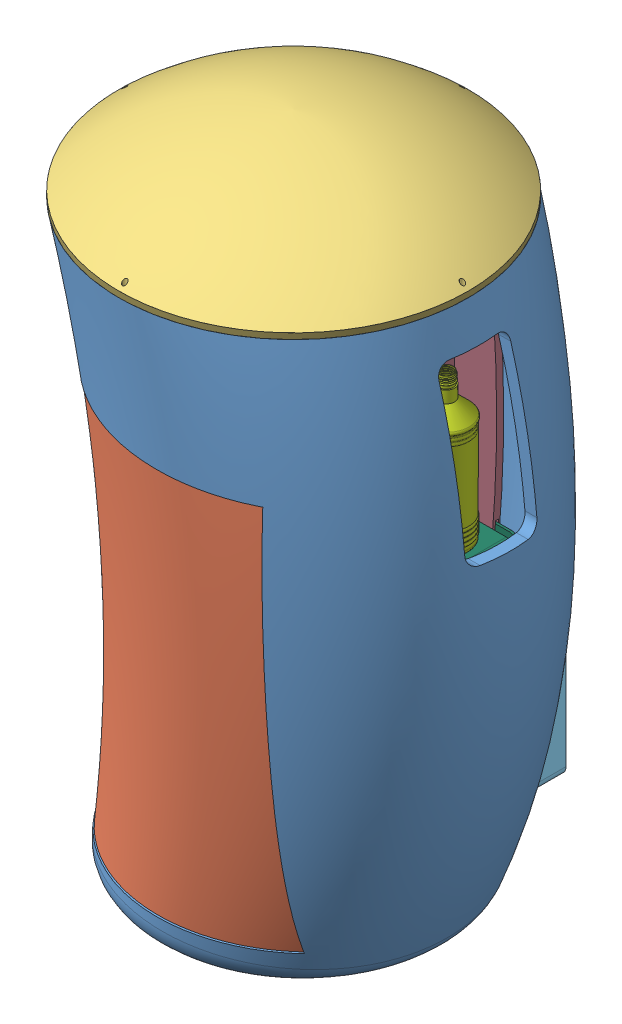
SolidWorks assembly Final assembly, configuration Default. Lengths in mm.
Overall size (714.59 1130 678.31).
22 component instances, 15 part files, 9 mates.
Components (placement in the parent):
- body-1: body [Default] at (238.4897 116.9189 1113.8319) size (714.59 1000.01 604.52)
- DooR (2)-1: DooR (2) [Default] at (237.093 116.9189 1110.2554) x (-1 0 0) z (0 0 -1) size (539.09 712.4 312.06)
- head-1: head [Default] at (238.4897 1126.9189 1113.8319) size (600 120 600)
- The shrinker-2: The shrinker [Default] at (195.4435 68.0364 733.0496) size (200 714.8 100)
  - bottle load-1: bottle load [Default] at (69.4638 76.8825 55.0523) x (1 0 0) z (0 0 -1) size (105 16 100)
  - support mat-1: support mat [Default] at (69.4638 54.8825 55.0523) size (142 362 90)
  - pressing point-1: pressing point [Default] at (69.4638 377.6793 55.0523) x (-1 0 0) z (0 0 -1) size (135 357.5 15)
  - Battery Water Bottle HDPE-1: Battery Water Bottle HDPE [Default] at (69.4638 66.0825 55.0523) size (81.4 253.7 81.4)
  - hand-1: hand [Default] at (69.4638 753.6793 55.0523) x (0 0 1) z (1 0 0) size (20 50 200)
  - top_shrinker-2: top_shrinker [Default] at (69.4638 368.6793 55.0523) x (-1 0 0) z (0 -1 0) size (110 90 29)
  - holder-1: holder [Default] at (107.0415 392.6793 55.0523) x (0 0 1) z (0 -1 0) size (30 15 9)
  - holder-2: holder [Default] at (31.8862 392.6793 55.0523) x (0 0 -1) z (0 -1 0) size (30 15 9)
  - guidage-1: guidage [Default] at (116.4638 58.2714 92.0523) x (0.67309 0 -0.73956) z (0.73956 0 0.67309) size (5 360 5)
  - guidage-2: guidage [Default] at (22.4638 58.2301 92.0523) x (0.059609 0 0.998222) z (-0.998222 0 0.059609) size (5 360 5)
  - guidage-3: guidage [Default] at (116.4638 56.8278 18.0523) x (0.363061 0 -0.931765) z (0.931765 0 0.363061) size (5 360 5)
  - guidage-4: guidage [Default] at (22.4638 55.7969 18.0523) x (0.648295 0 -0.761389) z (0.761389 0 0.648295) size (5 360 5)
- plate_for_electronics-1: plate_for_electronics [Default] at (238.4897 1116.9189 1113.8319) size (600 10 600)
- chamber_product2-1: chamber_product2 [Default] at (96.9579 614.8492 1278.3882) x (0 0 -1) z (1 0 0) size (150 398 116)
  - base_product2-1: base_product2 [Default] at (164.5564 96.0696 403.5318) x (-1 0 0) z (0 0 -1) size (142 396 88.73)
  - arbre servo-1: arbre servo [Default] at (85.5564 113.0696 365.5318) x (0 0 -1) z (1 0 0) size (8 8 150)
  - bottle base_product 2-2: bottle base_product 2 [Default] at (164.1814 126.0696 408.5318) x (-1 0 0) z (0 0 1) size (135.25 22 100)
  - Battery Water Bottle HDPE-2: Battery Water Bottle HDPE [Default] at (164.5564 122.7501 403.5318) x (-0.998313 0 -0.058067) z (0.058067 0 -0.998313) size (81.4 253.7 81.4)
Mates (geometry in assembly coordinates):
- Coincident1: coincident anti-aligned: plane of body-1 through (38.4897 881.9189 1113.8319) normal (1 0 0); plane of DooR (2)-1 through (38.4897 881.9189 808.3186) normal (-1 0 0)
- Coincident2: coincident anti-aligned: plane of body-1 through (38.4897 181.9189 1113.8319) normal (0 1 0); plane of DooR (2)-1 through (38.4897 181.9189 808.3186) normal (0 -1 0)
- Coincident9: coincident aligned: plane of body-1 through (238.4897 116.9189 1113.8319) normal (0 -1 0); plane of The shrinker-2/support mat-1 through (319.9074 116.9189 743.1019) normal (0 -1 0)
- Lock1: lock: unknown of body-1; unknown of DooR (2)-1
- Coincident10: coincident anti-aligned: circle of head-1; circle of plate_for_electronics-1
- Concentric1: concentric aligned: circle of body-1; circle of plate_for_electronics-1
- Coincident13: coincident anti-aligned: plane of body-1 through (238.4897 1116.9189 1113.8319) normal (0 1 0); plane of plate_for_electronics-1 through (238.4897 1116.9189 1113.8319) normal (0 -1 0)
- Concentric6: concentric aligned: circle of plate_for_electronics-1; circle of chamber2-1/trial-1
- Coincident17: coincident anti-aligned: plane of plate_for_electronics-1 through (238.4897 1116.9189 1113.8319) normal (0 -1 0); plane of chamber2-1/trial-1 through (545.4897 1116.9189 1113.8319) normal (0 1 0)
